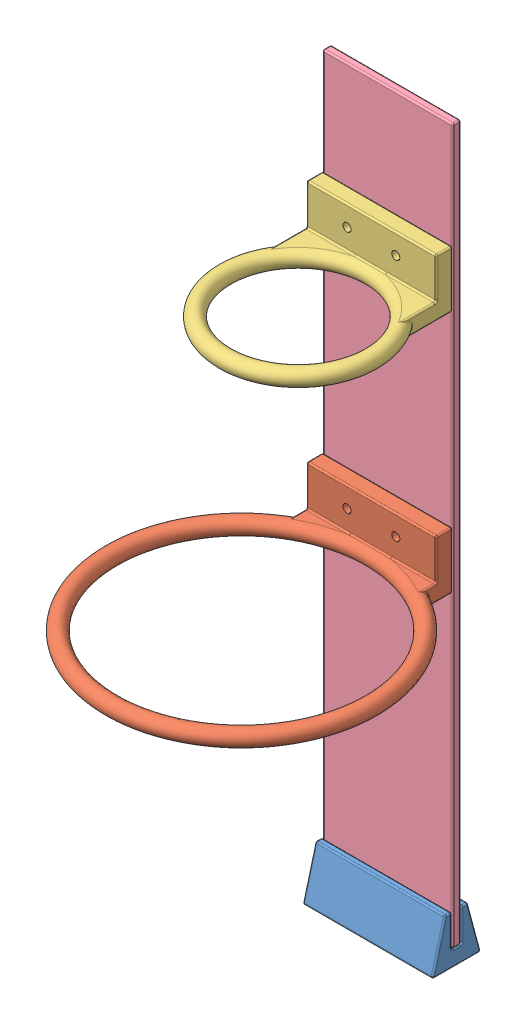
SolidWorks assembly Basket, configuration Default. Lengths in mm.
Overall size (170 450 192.2).
4 component instances, 4 part files, 9 mates.
Components (placement in the parent):
- Stand__Holder-1: Stand__Holder [Default] at (15.4712 28.6643 67.699) size (80 30 29.4)
- Big__Basket-1: Big__Basket [Default] at (15.4712 233.6643 160.199) x (0 0 1) z (-1 0 0) size (175 35.22 170)
- Small__Basket-1: Small__Basket [Default] at (15.4712 383.6643 125.199) x (0 0 1) z (-1 0 0) size (105 35.33 100)
- Basket__Frame-1: Basket__Frame [Default] at (15.4712 258.6643 67.699) x (0 0 1) z (-1 0 0) size (5 440 80)
Mates (geometry in assembly coordinates):
- Width1: width anti-aligned: plane of Basket__Frame-1 through (-24.5288 478.6643 70.199) normal (-1 0 0); plane of Basket__Frame-1 through (55.4712 478.6643 70.199) normal (1 0 0); plane of Stand__Holder-1 through (55.4712 28.6643 67.699) normal (1 0 0); plane of Stand__Holder-1 through (-24.5288 28.6643 67.699) normal (-1 0 0)
- Width2: width aligned: plane of Basket__Frame-1 through (15.4712 258.6643 65.199) normal (0 0 -1); plane of Basket__Frame-1 through (15.4712 258.6643 70.199) normal (0 0 1); plane of Stand__Holder-1 through (55.4712 58.6643 70.699) normal (0 0 -1); plane of Stand__Holder-1 through (55.4712 58.6643 64.699) normal (0 0 1)
- Coincident1: coincident anti-aligned: plane of Stand__Holder-1 through (55.4712 38.6643 70.699) normal (0 1 0); plane of Basket__Frame-1 through (-24.5288 38.6643 70.199) normal (0 -1 0)
- Coincident2: coincident anti-aligned: plane of Big__Basket-1 through (55.4712 198.6975 70.199) normal (0 0 -1); plane of Basket__Frame-1 through (15.4712 258.6643 70.199) normal (0 0 1)
- Coincident3: coincident: plane of Small__Basket-1 through (55.4712 234.0307 70.199) normal (0 0 -1); plane of Basket__Frame-1 through (15.4712 258.6643 70.199) normal (0 0 1)
- Width3: width aligned: plane of Basket__Frame-1 through (-24.5288 478.6643 70.199) normal (-1 0 0); plane of Big__Basket-1 through (55.4712 478.6643 70.199) normal (1 0 0); plane of Basket__Frame-1 through (-24.5288 173.6975 160.199) normal (-1 0 0); plane of Big__Basket-1 through (55.4712 198.6975 70.199) normal (1 0 0)
- Coincident4: coincident: plane of Big__Basket-1 through (55.4712 263.6643 70.199) normal (1 0 0); plane of Small__Basket-1 through (55.4712 234.0307 70.199) normal (1 0 0)
- Distance1: distance = 200 mm aligned: plane of Stand__Holder-1 through (55.4712 28.6643 82.699) normal (0 -1 0); plane of Big__Basket-1 through (15.4712 228.6643 160.199) normal (0 -1 0)
- Distance2: distance = 350 mm aligned: plane of Small__Basket-1 through (15.4712 378.6643 125.199) normal (0 -1 0); plane of Stand__Holder-1 through (55.4712 28.6643 82.699) normal (0 -1 0)
